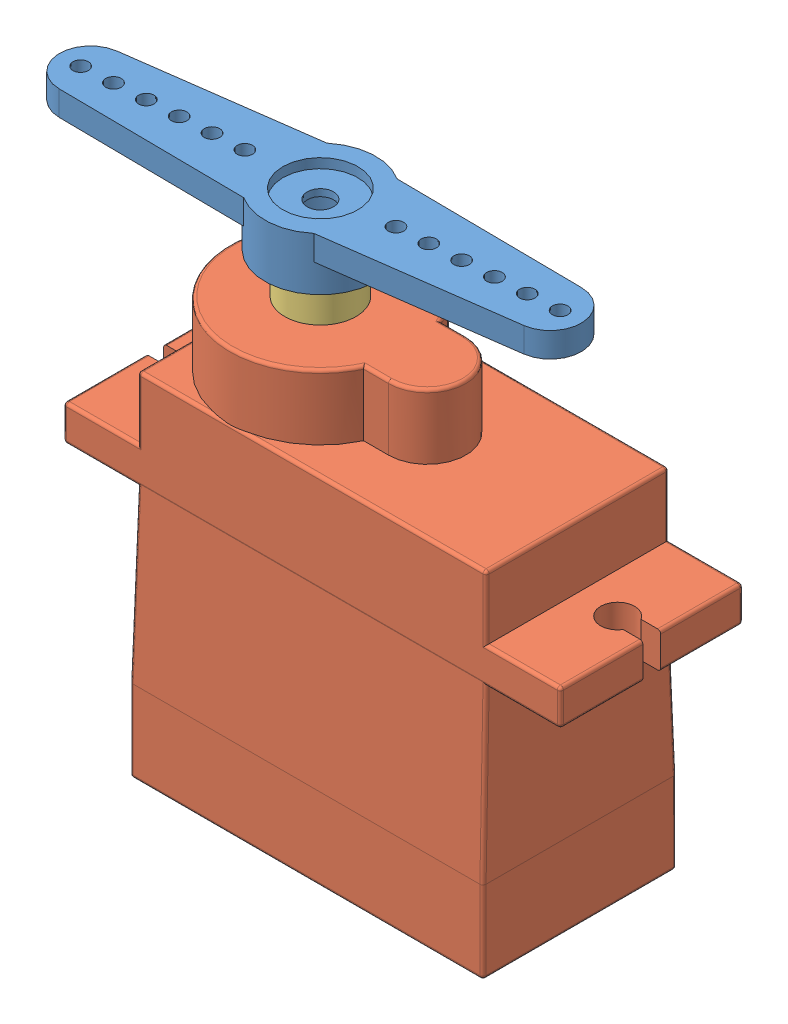
SolidWorks assembly MicroServo9g, configuration Default. Lengths in mm.
Overall size (37.59 32.83 12.52).
3 component instances, 3 part files, 3 mates.
Components (placement in the parent):
- horn-1: horn [Default] at (-10.4236 11.2587 -6.7554) x (0.998044 0 -0.062513) z (0.062513 0 0.998044) size (32 3.43 7.16)
- MicroServo9g2-1: MicroServo9g2 [Default] at (-10.804 8.8987 -7.1127) size (32.1 26.81 12.52)
- MicroServo9g4-1: MicroServo9g4 [Default] at (-10.804 8.8987 -7.1127) size (4.6 2.6 4.6)
Mates (geometry in assembly coordinates):
- Coincident1: coincident aligned: circle of horn-1; circle of MicroServo9g4-1
- Concentric4: concentric aligned: circle of MicroServo9g2-1; circle of MicroServo9g4-1
- Coincident2: coincident anti-aligned: plane of MicroServo9g2-1 through (-10.706 19.4987 -19.4902) normal (0 1 0); plane of MicroServo9g4-1 through (-7.25 19.4987 -10.6667) normal (0 -1 0)
